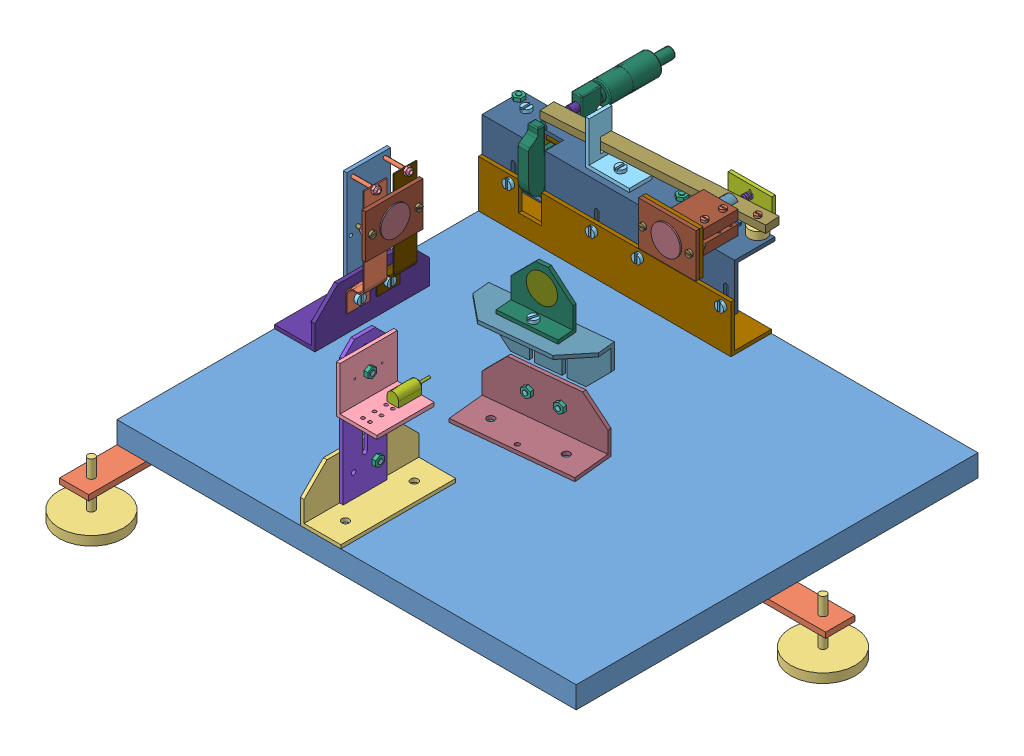
SolidWorks assembly Interferômetro Versão B, configuration Default. Lengths in mm.
Overall size (478.55 177.69 500.25).
108 component instances, 42 part files, 19 mates.
Components (placement in the parent):
- Baser de Granito-1: Baser de Granito [Default] at (68.0237 -84.1328 21.2634) size (400 19 350)
- Pé de 3 pontos-1: Pé de 3 pontos [Default] at (-331.9763 -88.8953 -158.7366) x (0 0 1) z (0 1 0) size (460 450 4.76)
- Suporte do LASER-1: Suporte do LASER [Default] at (-174.0544 -52.7769 -37.1706) x (0 0 -1) z (1 0 0) size (100 123.12 235.92)
  - Base do LASER-1: Base do LASER [Default] at (-58.434 -9.2309 37.1061) size (100 41.23 35.2)
  - Base do LASER 2-1: Base do LASER 2 [Default] at (-33.434 63.8941 43.3561) size (50 41.23 35.2)
  - Parafuso Padrao M4 16-1: Parafuso Padrao M4 16 [Default] at (1.566 10.7691 1.9081) x (-0.976419 -0.215883 0) z (0.215883 -0.976419 0) size (8 13 8)
  - Porca M4-1: Porca M4 [Default] at (1.566 10.7691 8.1581) x (1 0 0) z (0 -1 0) size (7.78 3.12 8.95)
  - Parafuso Padrao M4 16-2: Parafuso Padrao M4 16 [Default] at (-8.434 84.0234 5.0331) x (1 0 0) z (0 1 0) size (8 13 8)
  - LASER-1: LASER [Default] at (16.566 68.8941 27.3561) x (0 0 1) z (-1 0 0) size (10 10 32)
  - Coluna do LASER-2: Coluna do LASER [Default] at (10.616 -9.2309 5.0331) size (38.1 120 3.12)
  - Porca M4-3: Porca M4 [Default] at (-18.434 10.7691 8.1581) x (1 0 0) z (0 -1 0) size (7.78 3.12 8.95) (suppressed, hidden)
  - Parafuso Padrao M4 16-3: Parafuso Padrao M4 16 [Default] at (-18.434 10.7691 1.9081) x (-0.976419 -0.215883 0) z (0.215883 -0.976419 0) size (8 13 8) (suppressed, hidden)
  - Porca M4 com grampo-1: Porca M4 com grampo [Default] at (-8.434 84.0234 12.0331) x (0 -1 0) z (-1 0 0) size (20 3.88 30) (hidden)
  - Parafuso 22-1: Parafuso 22 [Default] at (-20.434 84.0234 12.0331) x (1 0 0) z (0 -1 0) size (3.2 5.55 3.24) (hidden)
  - Parafuso 22-2: Parafuso 22 [Default] at (3.566 84.0234 12.0331) x (1 0 0) z (0 -1 0) size (3.2 5.55 3.24) (hidden)
  - Porca M4-4: Porca M4 [Default] at (-8.434 84.0234 11.2831) x (1 0 0) z (0 -1 0) size (7.78 3.12 8.95)
- Espelho regulavel 2-1: Espelho regulavel 2 [Default] at (-194.6649 -55.8584 -280.9251) x (-1 0 0) z (0 0 -1) size (220.23 109.35 144.91)
  - Base fixa do espelho Regulavel-1: Base fixa do espelho Regulavel [Default] at (-82.6886 -6.1494 47.8115) size (220 41.23 35.2)
  - Base do espelho Regulavel-1: Base do espelho Regulavel [Default] at (117.3114 58.8506 50.9365) x (-1 0 0) z (0 0 1) size (220 41.23 35.2)
  - Trilo de Nylon-1: Trilo de Nylon [Default] at (-65.6886 61.9756 35.7385) x (-1 0 0) z (0 0 -1) size (30 20 30)
  - Alvanca de reducao-1: Alvanca de reducao [Default] at (102.5106 75.1506 43.4966) x (0.997978 0 -0.063556) z (-0.063556 0 -0.997978) size (185 6.35 14.7)
  - Espelho-1: Espelho [Default] at (-47.6886 71.9756 -9.2928) x (0.387514 -0.921864 0) z (0 0 1) size (25.4 25.4 3)
  - Guia linear-3: Guia linear [Default] at (-47.6886 71.9756 48.3322) x (-1 0 0) z (0 0 -1) size (12.7 12.7 60)
  - Micrometro-1: Micrometro [Default] at (96.6114 48.8506 52.9365) x (0 0 1) z (-1 0 0) size (128.44 56.67 19.2)
  - Base do micrometro A-1: Base do micrometro A [Default] at (47.1134 55.7256 50.9365) x (0 0 -1) z (-1 0 0) size (25 41.23 35.2)
  - Base do micrometro A-2: Base do micrometro A [Default] at (137.3114 55.7256 25.9365) x (0 0 1) z (1 0 0) size (25 41.23 35.2)
  - Eixo do micrometro-1: Eixo do micrometro [Default] at (92.1114 71.9235 96.1322) x (0.963366 0.268189 0) z (-0.268189 0.963366 0) size (7 50 7)
  - Parafuso Padrao M4-1: Parafuso Padrao M4 [Default] at (79.1864 22.6256 38.4365) x (0 1 0) z (0 0 1) size (8 33 8)
  - Porca M4-1: Porca M4 [Default] at (108.3634 22.6256 38.4365) x (0 1 0) z (0 0 1) size (7.78 3.12 8.95)
  - Parafuso Padrao M4-2: Parafuso Padrao M4 [Default] at (79.1864 51.1928 38.4365) x (0 1 0) z (0 0 1) size (8 33 8)
  - Porca M4-2: Porca M4 [Default] at (108.3634 51.1928 38.4365) x (0 1 0) z (0 0 1) size (7.78 3.12 8.95)
  - Parafuso Padrao M4 16-1: Parafuso Padrao M4 16 [Default] at (121.2749 61.9756 38.4365) size (8 13 8)
  - Parafuso Padrao M4 16-2: Parafuso Padrao M4 16 [Default] at (63.1499 61.9756 38.4365) size (8 13 8)
  - Porca M4-3: Porca M4 [Default] at (121.2749 52.6006 38.4365) size (7.78 3.12 8.95)
  - Porca M4-4: Porca M4 [Default] at (63.1499 52.6006 38.4365) size (7.78 3.12 8.95)
  - Parafuso Padrao M3-1: Parafuso Padrao M3 [Default] at (-63.1886 56.8506 21.7385) x (-0.377487 0 -0.926015) z (0 1 0) size (5.45 5.45 12)
  - Parafuso Padrao M3-2: Parafuso Padrao M3 [Default] at (-63.1886 56.8506 31.7385) x (-0.377487 0 -0.926015) z (0 1 0) size (5.45 5.45 12)
  - Parafuso Padrao M3-3: Parafuso Padrao M3 [Default] at (-38.1886 56.8506 21.7385) x (-0.377487 0 -0.926015) z (0 1 0) size (5.45 5.45 12)
  - Parafuso Padrao M3-4: Parafuso Padrao M3 [Default] at (-38.1886 56.8506 31.7385) x (-0.377487 0 -0.926015) z (0 1 0) size (5.45 5.45 12)
  - Parafuso Padrao M3 20-1: Parafuso Padrao M3 20 [Default] at (-59.6886 83.9756 12.7385) x (1 0 0) z (0 -1 0) size (5.45 5.45 22)
  - Parafuso Padrao M3 20-2: Parafuso Padrao M3 20 [Default] at (-59.6886 83.9756 28.7385) x (1 0 0) z (0 -1 0) size (5.45 5.45 22)
  - Parafuso Padrao M4 16-3: Parafuso Padrao M4 16 [Default] at (-75.1886 25.7256 12.6135) x (1 0 0) z (0 1 0) size (8 13 8)
  - Parafuso Padrao M4 16-4: Parafuso Padrao M4 16 [Default] at (-2.6886 25.7256 12.6135) x (1 0 0) z (0 1 0) size (8 13 8)
  - Parafuso Padrao M4 16-5: Parafuso Padrao M4 16 [Default] at (37.3114 25.7256 12.6135) x (1 0 0) z (0 1 0) size (8 13 8)
  - Parafuso Padrao M4 16-6: Parafuso Padrao M4 16 [Default] at (109.8114 25.7256 12.6135) x (1 0 0) z (0 1 0) size (8 13 8)
  - Porca M4-5: Porca M4 [Default] at (37.3114 25.7256 21.9885) x (1 0 0) z (0 1 0) size (7.78 3.12 8.95)
  - Porca M4-6: Porca M4 [Default] at (109.8114 25.7256 21.9885) x (1 0 0) z (0 1 0) size (7.78 3.12 8.95)
  - Porca M4-7: Porca M4 [Default] at (-75.1886 25.7256 21.9885) x (1 0 0) z (0 1 0) size (7.78 3.12 8.95)
  - Porca M4-8: Porca M4 [Default] at (-2.6886 25.7256 21.9885) x (1 0 0) z (0 1 0) size (7.78 3.12 8.95)
  - Bucha-1: Bucha [Default] at (-72.6886 68.7756 45.9365) x (1 0 0) z (0 -1 0) size (15 15 6.8)
  - Parafuso Padrao M3 20-3: Parafuso Padrao M3 20 [Default] at (-72.6886 77.1506 45.9365) x (1 0 0) z (0 -1 0) size (5.45 5.45 22)
  - Porca M3-1: Porca M3 [Default] at (-72.6886 58.8506 45.9365) x (-0.837169 0 -0.546944) z (-0.546944 0 0.837169) size (6.52 3.8 6.82)
  - Suporte da alavanca-1: Suporte da alavanca [Default] at (14.2114 61.9756 40.9479) x (-1 0 0) z (0 0 -1) size (38.1 38.1 20)
  - Parafuso Padrao M4 16-7: Parafuso Padrao M4 16 [Default] at (31.6989 65.1006 30.9479) size (8 13 8)
  - Porca M4-9: Porca M4 [Default] at (31.6989 55.7256 30.9479) size (7.78 3.12 8.95)
  - Haste M4 Longa 2-1: Haste M4 Longa 2 [Default] at (133.3114 -9.2744 43.8115) size (4 75 4)
  - Porca M4-10: Porca M4 [Default] at (133.3114 61.9756 43.8115) size (7.78 3.12 8.95)
  - Porca M4-11: Porca M4 [Default] at (133.3114 52.6006 43.8115) size (7.78 3.12 8.95)
  - Haste M4 Longa 2-2: Haste M4 Longa 2 [Default] at (-12.6886 -9.2744 39.8115) size (4 75 4)
  - Porca M4-13: Porca M4 [Default] at (-12.6886 61.9756 39.8115) size (7.78 3.12 8.95)
  - Porca M4-14: Porca M4 [Default] at (-12.6886 55.7256 39.8115) size (7.78 3.12 8.95)
  - Esticador da mola-1: Esticador da mola [Default] at (-64.9597 55.7256 39.0615) x (0 0 -1) z (1 0 0) size (30 20 38.1)
  - Mola do guia linear-1: Mola do guia linear [Default] at (-45.9871 67.7595 66.2365) x (-0.923728 -0.383049 0) z (0 0 -1) size (6.35 5.57 11.5)
  - Parafuso Padrao M3-8: Parafuso Padrao M3 [Default] at (-35.3778 63.9756 44.0615) x (1 0 0) z (0 -1 0) size (5.45 5.45 12)
  - Parafuso Padrao M3-9: Parafuso Padrao M3 [Default] at (-56.4416 63.9756 44.0615) x (1 0 0) z (0 -1 0) size (5.45 5.45 12)
  - Porca M3-2: Porca M3 [Default] at (-35.3778 55.7256 44.0615) x (-0.837169 0 -0.546944) z (-0.546944 0 0.837169) size (6.52 3.8 6.82)
  - Porca M3-3: Porca M3 [Default] at (-56.4416 55.7256 44.0615) x (-0.837169 0 -0.546944) z (-0.546944 0 0.837169) size (6.52 3.8 6.82)
  - Coluna do espelho movel-1: Coluna do espelho movel [Default] at (-22.6886 52.9256 -1.6678) x (0 -1 0) z (0 0 -1) size (38.1 50 3.12)
  - Parafuso Padrao M5-1: Parafuso Padrao M5 [Default] at (-47.6886 71.9756 -4.7928) x (1 0 0) z (0 -1 0) size (10 12 9.8)
  - Suporte do Espelho-1: Suporte do Espelho [Default] at (-22.6886 91.0256 -4.7928) x (0 1 0) z (0 0 1) size (38.1 50 3.18)
  - Parafuso Padrao M3 10-1: Parafuso Padrao M3 10 [Default] at (-67.7386 71.9756 -9.9728) size (5.45 5.45 14)
  - Parafuso Padrao M3 10-2: Parafuso Padrao M3 10 [Default] at (-27.1795 71.9756 -9.9728) size (5.45 5.45 14)
  - Porca M3-4: Porca M3 [Default] at (-67.7386 71.9756 -1.6678) x (1 0 0) z (0 -1 0) size (6.52 3.8 6.82)
  - Porca M3-5: Porca M3 [Default] at (-27.1795 71.9756 -1.6678) x (1 0 0) z (0 -1 0) size (6.52 3.8 6.82)
- Sup_Divisor de feixe-1: Sup_Divisor de feixe [Default] at (-131.5106 -64.9103 -154.738) x (0.99498 0 -0.100071) z (0.100071 0 0.99498) size (100 125.92 41.32)
  - Base do divisor-1: Base do divisor [Default] at (-56.6739 2.9025 27.9341) size (100 41.23 35.2)
  - Base do divisor B-1: Base do divisor B [Default] at (43.3261 81.3513 24.8091) x (-1 0 0) z (0 0 1) size (100 41.23 35.2)
  - Suporte do Divisor-1: Suporte do Divisor [Default] at (-32.1193 87.6013 30.6764) x (0.999823 0 0.018792) z (-0.018792 0 0.999823) size (50 41.23 17.19)
  - Parafuso Padrao M4 16-1: Parafuso Padrao M4 16 [Default] at (6.3761 22.9025 -10.3889) x (1 0 0) z (0 1 0) size (8 13 8)
  - Parafuso Padrao M4 16-2: Parafuso Padrao M4 16 [Default] at (-19.7239 22.9025 -10.3889) x (0.998184 -0.06024 0) z (0.06024 0.998184 0) size (8 13 8)
  - Parafuso Padrao M4 16-3: Parafuso Padrao M4 16 [Default] at (-6.6739 87.6013 7.2101) x (0.93764 0 0.347608) z (-0.347608 0 0.93764) size (8 13 8)
  - Porca M4-1: Porca M4 [Default] at (-19.7239 22.9025 -4.1389) x (1 0 0) z (0 -1 0) size (7.78 3.12 8.95)
  - Porca M4-2: Porca M4 [Default] at (6.3761 22.9025 -1.0139) x (1 0 0) z (0 1 0) size (7.78 3.12 8.95)
  - Porca M4-3: Porca M4 [Default] at (-6.6739 78.2263 7.2101) x (0.202843 0 0.979211) z (-0.979211 0 0.202843) size (7.78 3.12 8.95)
  - Divisor de feixe-1: Divisor de feixe [Default] at (-6.4647 107.6013 -3.9206) x (0.999823 0.000014 0.018792) z (-0.018792 0 0.999823) size (25.4 25.4 3)
- Suporte do Espelho Fixo-1: Suporte do Espelho Fixo [Default] at (-299.9274 -56.6546 -162.1076) x (0 0 1) z (-1 0 0) size (100 118.13 56.38)
  - Base do esplho fixo-1: Base do esplho fixo [Default] at (-53.8426 -5.3532 32.0489) size (100 41.23 35.2)
  - Mola chata-1: Mola chata [Default] at (-6.8926 7.1468 -4.1491) x (0 0 1) z (0 -1 0) size (16 20 100)
  - Coluna-1: Coluna [Default] at (15.2074 34.6468 -0.0241) size (38.1 100 3.12)
  - Mola chata_espelhada-1: Mola chata_espelhada [Default] at (19.2074 7.1468 -4.1491) x (0 0 1) z (0 -1 0) size (16 20 100)
  - Suporte do Espelho-1: Suporte do Espelho [Default] at (-28.8426 56.3037 -19.1491) x (0 -1 0) z (0 0 1) size (38.1 50 3.18)
  - Parafuso Padrao M4 16-1: Parafuso Padrao M4 16 [Default] at (-16.8926 14.6468 -4.1491) x (1 0 0) z (0 1 0) size (8 13 8)
  - Parafuso Padrao M4 16-2: Parafuso Padrao M4 16 [Default] at (9.2074 14.6468 -4.1491) x (1 0 0) z (0 1 0) size (8 13 8)
  - Porca M4-1: Porca M4 [Default] at (9.2074 14.6468 6.2259) x (1 0 0) z (0 1 0) size (7.78 3.12 8.95)
  - Porca M4-2: Porca M4 [Default] at (-16.8926 14.6468 6.2259) x (1 0 0) z (0 1 0) size (7.78 3.12 8.95)
  - Parafuso Padrao M3 10-1: Parafuso Padrao M3 10 [Default] at (-24.3517 75.3537 -24.3291) x (-0.944047 -0.32981 0) z (0 0 1) size (5.45 5.45 14)
  - Parafuso Padrao M3 10-2: Parafuso Padrao M3 10 [Default] at (16.2074 75.3537 -24.3291) size (5.45 5.45 14)
  - Porca M3-1: Porca M3 [Default] at (16.2074 75.3537 -18.1491) x (1 0 0) z (0 -1 0) size (6.52 3.8 6.82)
  - Porca M3-2: Porca M3 [Default] at (-24.3517 75.3537 -18.1491) x (0.940985 0.338447 0) z (0.338447 -0.940985 0) size (6.52 3.8 6.82)
  - Espelho-1: Espelho [Default] at (-3.8426 75.3537 -23.3291) size (25.4 25.4 3)
  - Parafuso Padrao M3 20-1: Parafuso Padrao M3 20 [Default] at (-17.8926 104.6468 5.1009) x (-0.923728 -0.383049 0) z (0 0 -1) size (5.45 5.45 22)
  - Parafuso Padrao M3 20-2: Parafuso Padrao M3 20 [Default] at (10.2074 104.6468 5.1009) x (-0.923728 -0.383049 0) z (0 0 -1) size (5.45 5.45 22)
  - Porca M3-3: Porca M3 [Default] at (10.2074 104.6468 -19.1491) x (1 0 0) z (0 1 0) size (6.52 3.8 6.82)
  - Porca M3-4: Porca M3 [Default] at (-17.8926 104.6468 -19.1491) x (1 0 0) z (0 1 0) size (6.52 3.8 6.82)
- Feixe de LASER-1: Feixe de LASER [Default] at (123.4017 16.3288 -166.7041) x (0 0 1) z (-1 0 0) size (1.6 1.6 400) (hidden)
- Pe_manipulo-1: Pe_manipulo [Default] at (-319.2763 -90.4001 56.2634) size (56.25 48 56.25)
- Pe_manipulo-3: Pe_manipulo [Default] at (103.0237 -90.4001 -158.7366) size (56.25 48 56.25)
- Pe_manipulo-4: Pe_manipulo [Default] at (-319.2763 -90.4001 -373.7366) size (56.25 48 56.25)
Mates (geometry in assembly coordinates):
- Coincident1: coincident anti-aligned: plane of Baser de Granito-1 through (68.0237 -84.1328 -328.7366) normal (0 -1 0); plane of Pé de 3 pontos-1 through (118.0237 -84.1328 71.2634) normal (0 1 0)
- Coincident2: coincident aligned: plane of Baser de Granito-1 through (-331.9763 -65.1328 21.2634) normal (-1 0 0); plane of Pé de 3 pontos-1 through (-331.9763 -84.1328 -388.7366) normal (-1 0 0)
- Distance1: distance = 50 mm: plane of Baser de Granito-1 through (68.0237 -65.1328 21.2634) normal (0 0 1); line of Pé de 3 pontos-1 through (-331.9763 -84.1328 71.2634) axis (1 0 0)
- Coincident4: coincident anti-aligned: plane of Baser de Granito-1 through (68.0237 -65.1328 -328.7366) normal (0 1 0); plane of Suporte do LASER-1/Base do LASER-1 through (-136.9483 -65.1328 -78.7366) normal (0 -1 0)
- Coincident5: coincident aligned: plane of Baser de Granito-1 through (68.0237 -65.1328 21.2634) normal (0 0 1); plane of Suporte do LASER-1/Base do LASER-1 through (-172.1463 -62.0078 21.2634) normal (0 0 1)
- Coincident6: coincident anti-aligned: plane of Baser de Granito-1 through (68.0237 -65.1328 -328.7366) normal (0 1 0); plane of Espelho regulavel 2-1/Base fixa do espelho Regulavel-1 through (-331.9763 -65.1328 -328.7366) normal (0 -1 0)
- Coincident7: coincident aligned: plane of Baser de Granito-1 through (68.0237 -65.1328 -328.7366) normal (0 0 -1); plane of Espelho regulavel 2-1/Base fixa do espelho Regulavel-1 through (-331.9763 -65.1328 -328.7366) normal (0 0 -1)
- Coincident8: coincident aligned: plane of Baser de Granito-1 through (-331.9763 -65.1328 21.2634) normal (-1 0 0); plane of Espelho regulavel 2-1/Base fixa do espelho Regulavel-1 through (-331.9763 -62.0078 -293.5386) normal (-1 0 0)
- Coincident9: coincident anti-aligned: plane of Baser de Granito-1 through (68.0237 -65.1328 -328.7366) normal (0 1 0); plane of Sup_Divisor de feixe-1/Base do divisor-1 through (-85.6066 -65.1328 -131.2797) normal (0 -1 0)
- Distance3: distance = 10 mm: line of Espelho regulavel 2-1/Base fixa do espelho Regulavel-1 through (-111.9763 -65.1328 -293.5386) axis (0 1 0); plane of Sup_Divisor de feixe-1/Base do divisor-1 through (-89.1289 -62.0078 -166.3011) normal (0.99498 0 -0.100071)
- Coincident12: coincident anti-aligned: plane of Baser de Granito-1 through (68.0237 -65.1328 -328.7366) normal (0 1 0); plane of Suporte do Espelho Fixo-1/Base do esplho fixo-1 through (-331.9763 -65.1328 -115.9502) normal (0 -1 0)
- Coincident13: coincident aligned: plane of Baser de Granito-1 through (-331.9763 -65.1328 21.2634) normal (-1 0 0); plane of Suporte do Espelho Fixo-1/Base do esplho fixo-1 through (-331.9763 -65.1328 -115.9502) normal (-1 0 0)
- Coincident14: coincident anti-aligned: plane of Suporte do Espelho Fixo-1/Espelho-1 through (-276.5983 18.6991 -165.9502) normal (1 0 0); plane of Feixe de LASER-1 through (-276.5983 16.3288 -166.7041) normal (-1 0 0)
- Concêntrico1: concentric anti-aligned: cylinder of Pé de 3 pontos-1 through (-319.2763 -88.8953 56.2634) axis (0 1 0) radius 3.125; cylinder of Pe_manipulo-1 through (-319.2763 -90.4001 56.2634) axis (0 -1 0) radius 3.125
- Distância1: distance = 20 mm anti-aligned: plane of Pe_manipulo-1 through (-316.1513 -108.8953 56.2634) normal (0 1 0); plane of Pé de 3 pontos-1 through (118.0237 -88.8953 71.2634) normal (0 -1 0)
- Concêntrico2: concentric anti-aligned: cylinder of Pé de 3 pontos-1 through (103.0237 -88.8953 -158.7366) axis (0 1 0) radius 3.125; cylinder of Pe_manipulo-3 through (103.0237 -90.4001 -158.7366) axis (0 -1 0) radius 3.125
- Distância2: distance = 20 mm anti-aligned: plane of Pe_manipulo-3 through (106.1487 -108.8953 -158.7366) normal (0 1 0); plane of Pé de 3 pontos-1 through (118.0237 -88.8953 71.2634) normal (0 -1 0)
- Concêntrico3: concentric anti-aligned: cylinder of Pé de 3 pontos-1 through (-319.2763 -88.8953 -373.7366) axis (0 1 0) radius 3.125; cylinder of Pe_manipulo-4 through (-319.2763 -90.4001 -373.7366) axis (0 -1 0) radius 3.125
- Distância3: distance = 20 mm anti-aligned: plane of Pe_manipulo-4 through (-316.1513 -108.8953 -373.7366) normal (0 1 0); plane of Pé de 3 pontos-1 through (118.0237 -88.8953 71.2634) normal (0 -1 0)
